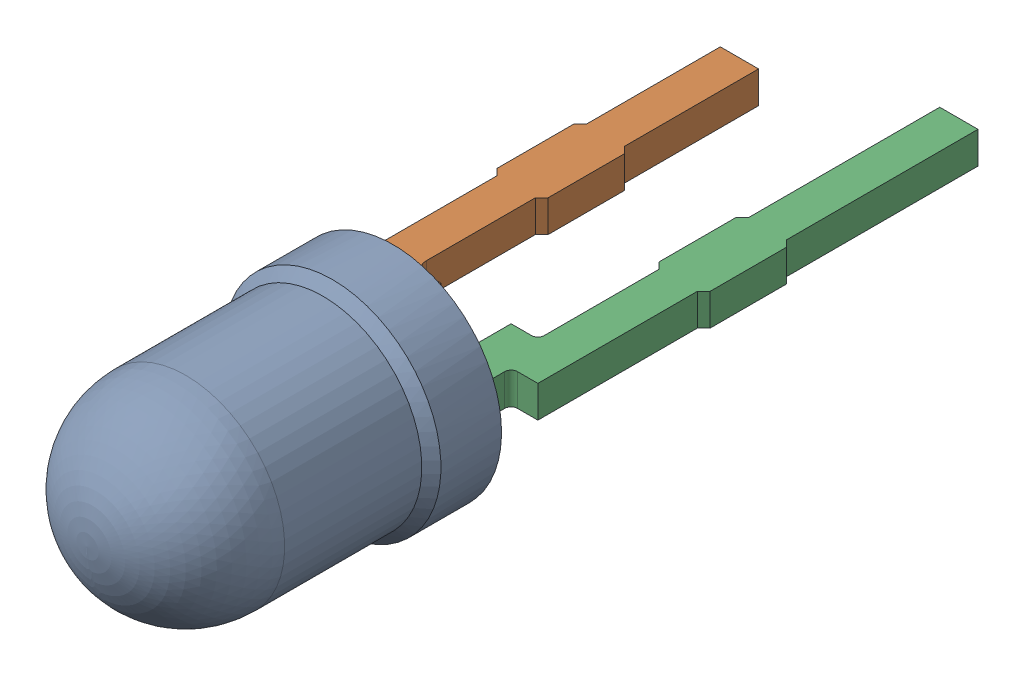
SolidWorks assembly User_Library-LA_3366_sc_1, configuration Default. Lengths in mm.
Overall size (3.4 3.4 12.4).
3 component instances, 3 part files, 0 mates.
Components (placement in the parent):
- User_Library-LA_3366_sc_BODY_amber-1: User_Library-LA_3366_sc_BODY_amber [Default] x (1 0 0) z (0 -1 0) size (3.4 4.8 3.4)
- User_Library-LA_3366_sc_LEAD_A_sc-1: User_Library-LA_3366_sc_LEAD_A_sc [Default] at (0 0.25 0) x (1 0 0) z (0 -1 0) size (1.12 6.7 0.5)
- User_Library-LA_3366_sc_LEAD_K_sc-1: User_Library-LA_3366_sc_LEAD_K_sc [Default] at (0 -0.25 0) x (-1 0 0) z (0 1 0) size (1.12 7.6 0.5)
